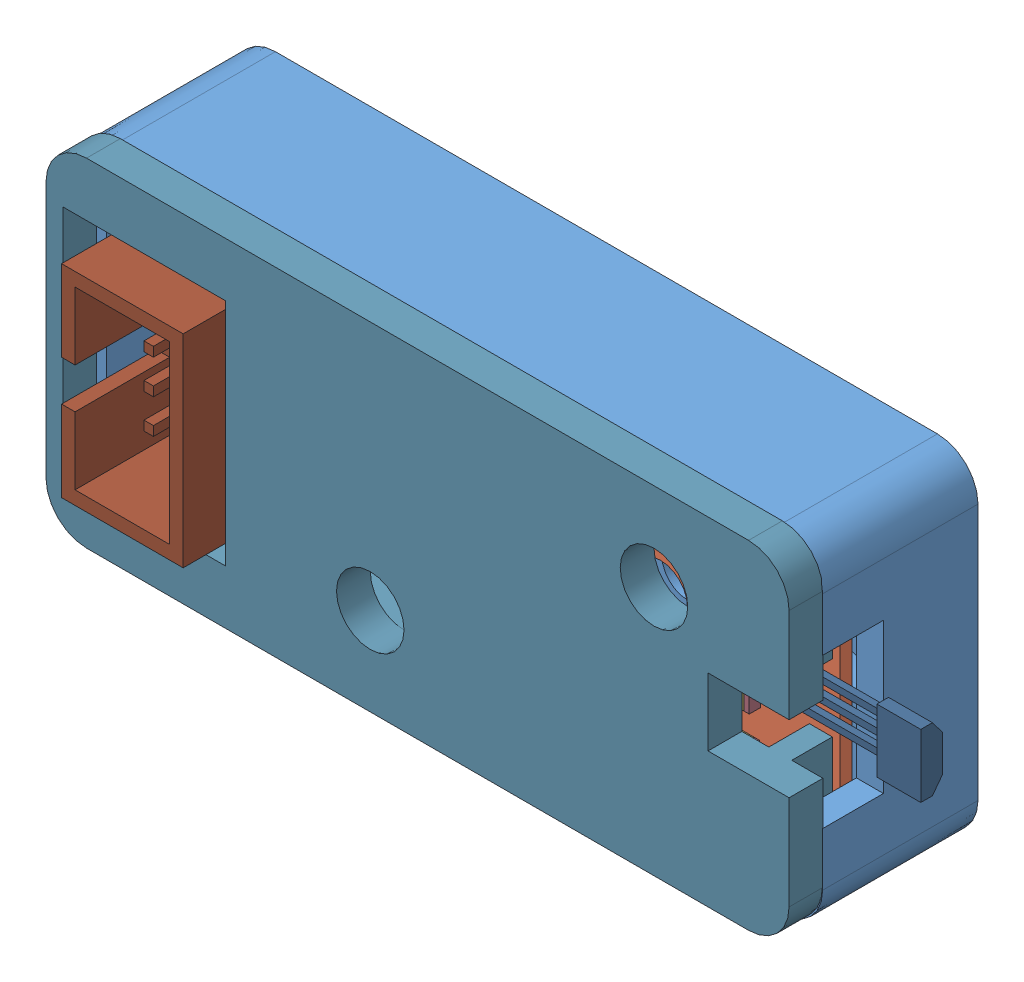
SolidWorks assembly case sensor hall, configuration Predeterminado. Lengths in mm.
Overall size (60.69 25.15 16.9).
96 component instances, 14 part files, 5 mates.
Components (placement in the parent):
- case sensor hall base-1: case sensor hall base [Predeterminado] at origin size (55 25 11.5)
- PCB SENSOR RPM.step-1: PCB SENSOR RPM.step [Predeterminado] at (-24.8272 -9.5 6.4042) size (58 20 12.6)
  - Board.step-1: Board.step [Predeterminado] at origin size (50 20 0.9)
    - Open CASCADE STEP translator 6.8 1.1.1.step-1: Open CASCADE STEP translator 6.8 1.1.1.step [Predeterminado] at (0 0 -0.9042) size (50 20 0.9)
  - U1.step-1: U1.step [Predeterminado] at origin size (4 5.1 1.65)
    - 6645362528.step-1: 6645362528.step [Predeterminado] at (30 5 0.1) size (4 5.1 1.65)
      - Extruded.step-1: Extruded.step [Predeterminado] at origin size (4 5.1 1.65)
  - R6.step-1: R6.step [Predeterminado] at origin size (2.1 1.35 0.35)
    - 6645354208.step-1: 6645354208.step [Predeterminado] at (22 6 0) size (1.3 1.35 0.35)
      - Extruded-0.step-1: Extruded-0.step [Predeterminado] at origin size (1.3 1.35 0.35)
    - 6645355488.step-1: 6645355488.step [Predeterminado] at (22.85 6 0) size (0.4 1.35 0.35)
      - Extruded-1.step-1: Extruded-1.step [Predeterminado] at origin size (0.4 1.35 0.35)
    - 6645355488.step-2: 6645355488.step [Predeterminado] at (21.15 6 0) size (0.4 1.35 0.35)
      - Extruded-1.step-1: Extruded-1.step [Predeterminado] at origin size (0.4 1.35 0.35)
  - R5.step-1: R5.step [Predeterminado] at origin size (2.1 1.35 0.35)
    - 6645354208.step-1: 6645354208.step [Predeterminado] at (43 13.5 0) size (1.3 1.35 0.35)
      - Extruded-0.step-1: Extruded-0.step [Predeterminado] at origin size (1.3 1.35 0.35)
    - 6645355488.step-1: 6645355488.step [Predeterminado] at (42.15 13.5 0) size (0.4 1.35 0.35)
      - Extruded-1.step-1: Extruded-1.step [Predeterminado] at origin size (0.4 1.35 0.35)
    - 6645355488.step-2: 6645355488.step [Predeterminado] at (43.85 13.5 0) size (0.4 1.35 0.35)
      - Extruded-1.step-1: Extruded-1.step [Predeterminado] at origin size (0.4 1.35 0.35)
  - R4.step-1: R4.step [Predeterminado] at origin size (2.1 1.35 0.35)
    - 6645354208.step-1: 6645354208.step [Predeterminado] at (22 18 0) size (1.3 1.35 0.35)
      - Extruded-0.step-1: Extruded-0.step [Predeterminado] at origin size (1.3 1.35 0.35)
    - 6645355488.step-1: 6645355488.step [Predeterminado] at (21.15 18 0) size (0.4 1.35 0.35)
      - Extruded-1.step-1: Extruded-1.step [Predeterminado] at origin size (0.4 1.35 0.35)
    - 6645355488.step-2: 6645355488.step [Predeterminado] at (22.85 18 0) size (0.4 1.35 0.35)
      - Extruded-1.step-1: Extruded-1.step [Predeterminado] at origin size (0.4 1.35 0.35)
  - R3.step-1: R3.step [Predeterminado] at origin size (2.1 1.35 0.35)
    - 6645354208.step-1: 6645354208.step [Predeterminado] at (43 10 0) size (1.3 1.35 0.35)
      - Extruded-0.step-1: Extruded-0.step [Predeterminado] at origin size (1.3 1.35 0.35)
    - 6645355488.step-1: 6645355488.step [Predeterminado] at (43.85 10 0) size (0.4 1.35 0.35)
      - Extruded-1.step-1: Extruded-1.step [Predeterminado] at origin size (0.4 1.35 0.35)
    - 6645355488.step-2: 6645355488.step [Predeterminado] at (42.15 10 0) size (0.4 1.35 0.35)
      - Extruded-1.step-1: Extruded-1.step [Predeterminado] at origin size (0.4 1.35 0.35)
  - R2.step-1: R2.step [Predeterminado] at origin size (1.35 2.1 0.35)
    - 6645356128.step-1: 6645356128.step [Predeterminado] at (22 15 0) size (1.35 1.3 0.35)
      - Extruded-2.step-1: Extruded-2.step [Predeterminado] at origin size (1.35 1.3 0.35)
    - 6645362048.step-1: 6645362048.step [Predeterminado] at (22 15.85 0) size (1.35 0.4 0.35)
      - Extruded-3.step-1: Extruded-3.step [Predeterminado] at origin size (1.35 0.4 0.35)
    - 6645362048.step-2: 6645362048.step [Predeterminado] at (22 14.15 0) size (1.35 0.4 0.35)
      - Extruded-3.step-1: Extruded-3.step [Predeterminado] at origin size (1.35 0.4 0.35)
  - R1.step-1: R1.step [Predeterminado] at origin size (2.1 1.35 0.35)
    - 6645354208.step-1: 6645354208.step [Predeterminado] at (22 11.5 0) size (1.3 1.35 0.35)
      - Extruded-0.step-1: Extruded-0.step [Predeterminado] at origin size (1.3 1.35 0.35)
    - 6645355488.step-1: 6645355488.step [Predeterminado] at (21.15 11.5 0) size (0.4 1.35 0.35)
      - Extruded-1.step-1: Extruded-1.step [Predeterminado] at origin size (0.4 1.35 0.35)
    - 6645355488.step-2: 6645355488.step [Predeterminado] at (22.85 11.5 0) size (0.4 1.35 0.35)
      - Extruded-1.step-1: Extruded-1.step [Predeterminado] at origin size (0.4 1.35 0.35)
  - LED2.step-1: LED2.step [Predeterminado] at origin size (2.1 1.35 1)
    - 6645356368.step-1: 6645356368.step [Predeterminado] at (21.155 3 0) size (0.41 1.35 1)
      - Extruded-4.step-1: Extruded-4.step [Predeterminado] at origin size (0.41 1.35 1)
    - 6645356368.step-2: 6645356368.step [Predeterminado] at (22.845 3 0) size (0.41 1.35 1)
      - Extruded-4.step-1: Extruded-4.step [Predeterminado] at origin size (0.41 1.35 1)
    - 6645351568.step-1: 6645351568.step [Predeterminado] at (22 3 0) size (1.28 1.35 1)
      - Extruded-5.step-1: Extruded-5.step [Predeterminado] at origin size (1.28 1.35 1)
  - LED1.step-1: LED1.step [Predeterminado] at origin size (2.1 1.35 1)
    - 6645356368.step-1: 6645356368.step [Predeterminado] at (43.845 17 0) size (0.41 1.35 1)
      - Extruded-4.step-1: Extruded-4.step [Predeterminado] at origin size (0.41 1.35 1)
    - 6645356368.step-2: 6645356368.step [Predeterminado] at (42.155 17 0) size (0.41 1.35 1)
      - Extruded-4.step-1: Extruded-4.step [Predeterminado] at origin size (0.41 1.35 1)
    - 6645351568.step-1: 6645351568.step [Predeterminado] at (43 17 0) size (1.28 1.35 1)
      - Extruded-5.step-1: Extruded-5.step [Predeterminado] at origin size (1.28 1.35 1)
  - HL1.step-1: HL1.step [Predeterminado] at origin size (10.25 4.69 3.05)
    - SENSOR_HALL.step-1: SENSOR_HALL.step [Predeterminado] at (57.9961 9.9999 2) x (0 1 0) z (-1 0 0) size (4.69 3.05 10.25)
  - CN1.step-1: CN1.step [Predeterminado] at origin size (9 15 12.6)
    - IDC_MACHO_6_VIAS.step-1: IDC_MACHO_6_VIAS.step [Predeterminado] at (5.8999 9.9001 0) x (0 1 0) z (0 0 1) size (15 9 12.6)
  - C4.step-1: C4.step [Predeterminado] at origin size (2.1 1.35 0.85)
    - 6645357808.step-1: 6645357808.step [Predeterminado] at (30 9.5 0) size (1.3 1.35 0.85)
      - Extruded-6.step-1: Extruded-6.step [Predeterminado] at origin size (1.3 1.35 0.85)
    - 6645361888.step-1: 6645361888.step [Predeterminado] at (29.15 9.5 0) size (0.4 1.35 0.85)
      - Extruded-7.step-1: Extruded-7.step [Predeterminado] at origin size (0.4 1.35 0.85)
    - 6645361888.step-2: 6645361888.step [Predeterminado] at (30.85 9.5 0) size (0.4 1.35 0.85)
      - Extruded-7.step-1: Extruded-7.step [Predeterminado] at origin size (0.4 1.35 0.85)
  - C3.step-1: C3.step [Predeterminado] at origin size (2.1 1.35 0.85)
    - 6645361888.step-1: 6645361888.step [Predeterminado] at (21.15 9 0) size (0.4 1.35 0.85)
      - Extruded-7.step-1: Extruded-7.step [Predeterminado] at origin size (0.4 1.35 0.85)
    - 6645361888.step-2: 6645361888.step [Predeterminado] at (22.85 9 0) size (0.4 1.35 0.85)
      - Extruded-7.step-1: Extruded-7.step [Predeterminado] at origin size (0.4 1.35 0.85)
    - 6645357808.step-1: 6645357808.step [Predeterminado] at (22 9 0) size (1.3 1.35 0.85)
      - Extruded-6.step-1: Extruded-6.step [Predeterminado] at origin size (1.3 1.35 0.85)
  - C2.step-1: C2.step [Predeterminado] at origin size (2.1 1.35 0.85)
    - 6645357808.step-1: 6645357808.step [Predeterminado] at (43.1 6.5 0) size (1.3 1.35 0.85)
      - Extruded-6.step-1: Extruded-6.step [Predeterminado] at origin size (1.3 1.35 0.85)
    - 6645361888.step-1: 6645361888.step [Predeterminado] at (42.25 6.5 0) size (0.4 1.35 0.85)
      - Extruded-7.step-1: Extruded-7.step [Predeterminado] at origin size (0.4 1.35 0.85)
    - 6645361888.step-2: 6645361888.step [Predeterminado] at (43.95 6.5 0) size (0.4 1.35 0.85)
      - Extruded-7.step-1: Extruded-7.step [Predeterminado] at origin size (0.4 1.35 0.85)
  - C1.step-1: C1.step [Predeterminado] at origin size (2.1 1.35 0.85)
    - 6645361888.step-1: 6645361888.step [Predeterminado] at (43.85 3 0) size (0.4 1.35 0.85)
      - Extruded-7.step-1: Extruded-7.step [Predeterminado] at origin size (0.4 1.35 0.85)
    - 6645361888.step-2: 6645361888.step [Predeterminado] at (42.15 3 0) size (0.4 1.35 0.85)
      - Extruded-7.step-1: Extruded-7.step [Predeterminado] at origin size (0.4 1.35 0.85)
    - 6645357808.step-1: 6645357808.step [Predeterminado] at (43 3 0) size (1.3 1.35 0.85)
      - Extruded-6.step-1: Extruded-6.step [Predeterminado] at origin size (1.3 1.35 0.85)
- case sensor hall tapa-1: case sensor hall tapa [Predeterminado] at (-0.0203 0.1465 12.4622) x (1 0 0) z (0 0 -1) size (55 25 5.5)
Mates (geometry in assembly coordinates):
- Coincidente1: coordinate: point of case sensor hall base-1; point of assembly
- Coincidente2: coincident: plane of case sensor hall base-1 through (11.5 0 5.5) normal (0 0 1); plane of PCB SENSOR RPM.step-1/Board.step-1/Open CASCADE STEP translator 6.8 1.1.1.step-1 through (-24.8272 -9.246 5.5) normal (0 0 -1)
- Coincidente3: coincident: plane of case sensor hall base-1 through (-25.5 10.5 10) normal (0 -1 0); plane of PCB SENSOR RPM.step-1/Board.step-1/Open CASCADE STEP translator 6.8 1.1.1.step-1 through (-24.5732 10.5 5.5) normal (0 1 0)
- Coincidente4: coincident: plane of case sensor hall base-1 through (-25.5 -10.5 8) normal (0 1 0); plane of case sensor hall tapa-1 through (-25.5 -10.5 5.8556) normal (0 -1 0)
- Coincidente5: coincident: plane of case sensor hall base-1 through (25.5 10.5 8) normal (-1 0 0); plane of case sensor hall tapa-1 through (25.5 -10.5 5.8556) normal (1 0 0)
